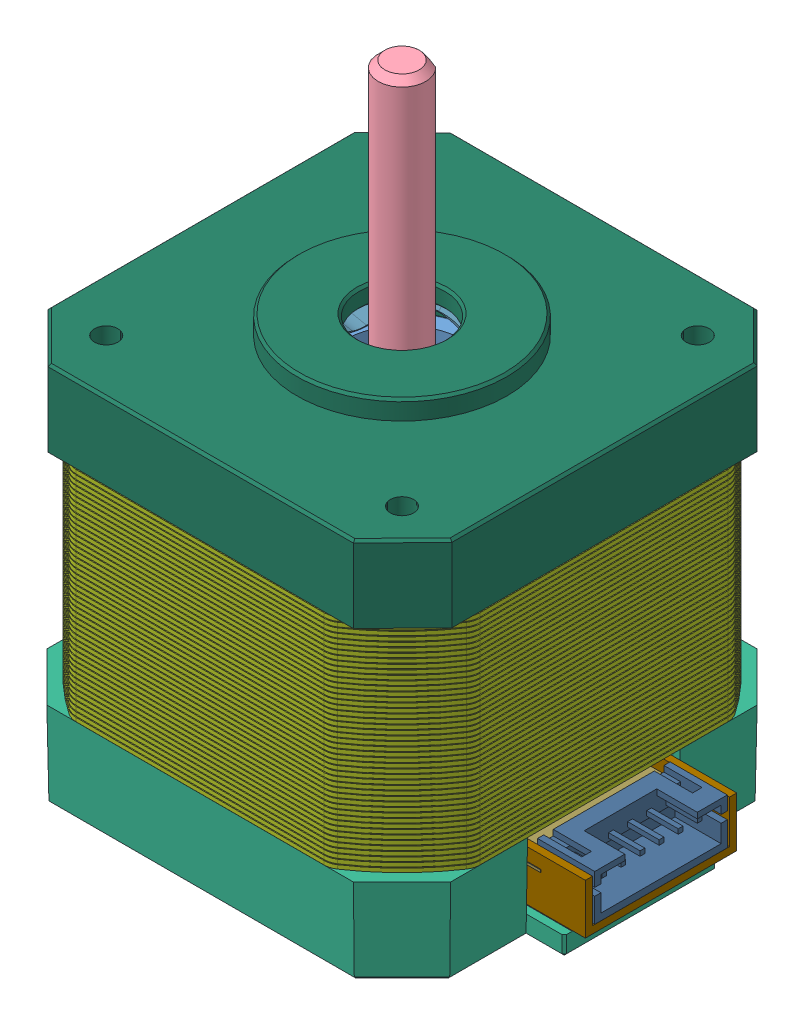
SolidWorks assembly Nema 17HS4401 Stepper Motor, configuration Default. Lengths in mm.
Overall size (48.31 65.73 42.31).
19 component instances, 15 part files, 2 mates.
Components (placement in the parent):
- BS 3469 - 02 - 5 x 16 x 5^Nema 17HS4401 Stepper Motor-1: BS 3469 - 02 - 5 x 16 x 5^Nema 17HS4401 Stepper Motor [Default] at (0.1619 -0.9089 -0.0473) x (0 -1 0) z (0.770185 0 -0.637821) size (5.01 16 16) (virtual)
- BS 3469 - 02 - 5 x 16 x 5^Nema 17HS4401 Stepper Motor-2: BS 3469 - 02 - 5 x 16 x 5^Nema 17HS4401 Stepper Motor [Default] at (0 -30.75 0) x (0 -1 0) z (-0.000016 0 1) size (5.01 16 16) (virtual)
- Nema 17 Plastic Spacer 2^Nema 17HS4401 Stepper Motor-1: Nema 17 Plastic Spacer 2^Nema 17HS4401 Stepper Motor [Default] at (-0.0395 -24.15 -0.0395) x (0.999985 0 -0.005516) z (0.005516 0 0.999985) size (9 3 9) (virtual)
- Nema 17 Plastic Spacer 1^Nema 17HS4401 Stepper Motor-1: Nema 17 Plastic Spacer 1^Nema 17HS4401 Stepper Motor [Default] at (0 -8.5 0) size (7.75 3 7.75) (virtual)
- Nema 17 shaft^Nema 17HS4401 Stepper Motor-1: Nema 17 shaft^Nema 17HS4401 Stepper Motor [Default] at origin size (5 59.5 5) (virtual)
- ANSI B27.7 - 5, E^Nema 17HS4401 Stepper Motor-1: ANSI B27.7 - 5, E^Nema 17HS4401 Stepper Motor [Default] at (0.0137 -25.65 2.4763) x (0.999985 0 -0.005516) z (0 -1 0) size (8.5 7.05 0.6) (virtual)
- Nema 17 Base Cap^Nema 17HS4401 Stepper Motor-1: Nema 17 Base Cap^Nema 17HS4401 Stepper Motor [Default] at (0 -37.5 0) x (1 0 0) z (0 0 -1) size (46.16 10 42.31) (virtual)
- Nema 17 Central Spacer^Nema 17HS4401 Stepper Motor-1: Nema 17 Central Spacer^Nema 17HS4401 Stepper Motor [Default] at (0 -20.5 0) size (42.3 23 42.3) (virtual)
- Nema 17 Stator Face^Nema 17HS4401 Stepper Motor-1: Nema 17 Stator Face^Nema 17HS4401 Stepper Motor [Default] at (0 -16 0) size (27.8 16 27.8) (virtual)
- Nema 17 plastic^Nema 17HS4401 Stepper Motor-1: Nema 17 plastic^Nema 17HS4401 Stepper Motor [Default] at (0 -21.8633 0) size (46.3 30.22 38.3) (virtual)
- S6B-PH-K-S^Nema 17HS4401 Stepper Motor-1: S6B-PH-K-S^Nema 17HS4401 Stepper Motor [Default] at (14.2 -27.906 -11.75) x (0 0 -1) z (1 0 0) size (13.9 8.2 6.5) (virtual)
- EN ISO 7045 - M3 x 25(1)^Nema 17HS4401 Stepper Motor-1: EN ISO 7045 - M3 x 25(1)^Nema 17HS4401 Stepper Motor [Default] at (15.5 -35.6028 -15.5) x (0 1 0) z (0 0 1) size (27.48 5.6 5.6) (virtual)
- EN ISO 7045 - M3 x 25(1)^Nema 17HS4401 Stepper Motor-2: EN ISO 7045 - M3 x 25(1)^Nema 17HS4401 Stepper Motor [Default] at (-15.5 -35.6168 15.5) x (0 1 0) z (0 0 1) size (27.48 5.6 5.6) (virtual)
- EN ISO 7045 - M3 x 25(1)^Nema 17HS4401 Stepper Motor-3: EN ISO 7045 - M3 x 25(1)^Nema 17HS4401 Stepper Motor [Default] at (15.5 -35.5356 15.5) x (0 1 0) z (0 0 1) size (27.48 5.6 5.6) (virtual)
- EN ISO 7045 - M3 x 25(1)^Nema 17HS4401 Stepper Motor-4: EN ISO 7045 - M3 x 25(1)^Nema 17HS4401 Stepper Motor [Default] at (-15.5 -35.7498 -15.5) x (0 1 0) z (0 0 1) size (27.48 5.6 5.6) (virtual)
- Nema 17 plastic protector^Nema 17HS4401 Stepper Motor-1: Nema 17 plastic protector^Nema 17HS4401 Stepper Motor [Default] at (0 -31 0) x (0 0 1) z (-1 0 0) size (39 0.25 23) (virtual)
- Nema 17 PCB^Nema 17HS4401 Stepper Motor-1: Nema 17 PCB^Nema 17HS4401 Stepper Motor [Default] at (-0.719 -35.4655 0.0967) x (0 0 1) z (-1 0 0) size (38 0.8 24.5) (virtual)
- Nema 17 Sprung Washer^Nema 17HS4401 Stepper Motor-1: Nema 17 Sprung Washer^Nema 17HS4401 Stepper Motor [Default] at (0 -0.3984 0) x (0.985654 0 0.168779) z (-0.168779 0 0.985654) size (15.5 2.12 15.5) (virtual)
- 17HS4401-Part5^Nema 17HS4401 Stepper Motor-1: 17HS4401-Part5^Nema 17HS4401 Stepper Motor [Default] at (0 2.5 0) x (0 0 1) z (-1 0 0) size (42.3 11 42.3) (virtual)
Mates (geometry in assembly coordinates):
- Coincident11: coordinate: point of Copy of Nema 17 shaft^Nema 17HS4401 Stepper Motor-1
- Distance3: distance = 40 mm anti-aligned: plane of Copy of 17HS4401-Part5^Nema 17HS4401 Stepper Motor-1 through (0 2.5 0) normal (0 1 0); plane of Nema 17 Base Cap-1 through (0 -37.5 0) normal (0 -1 0)
